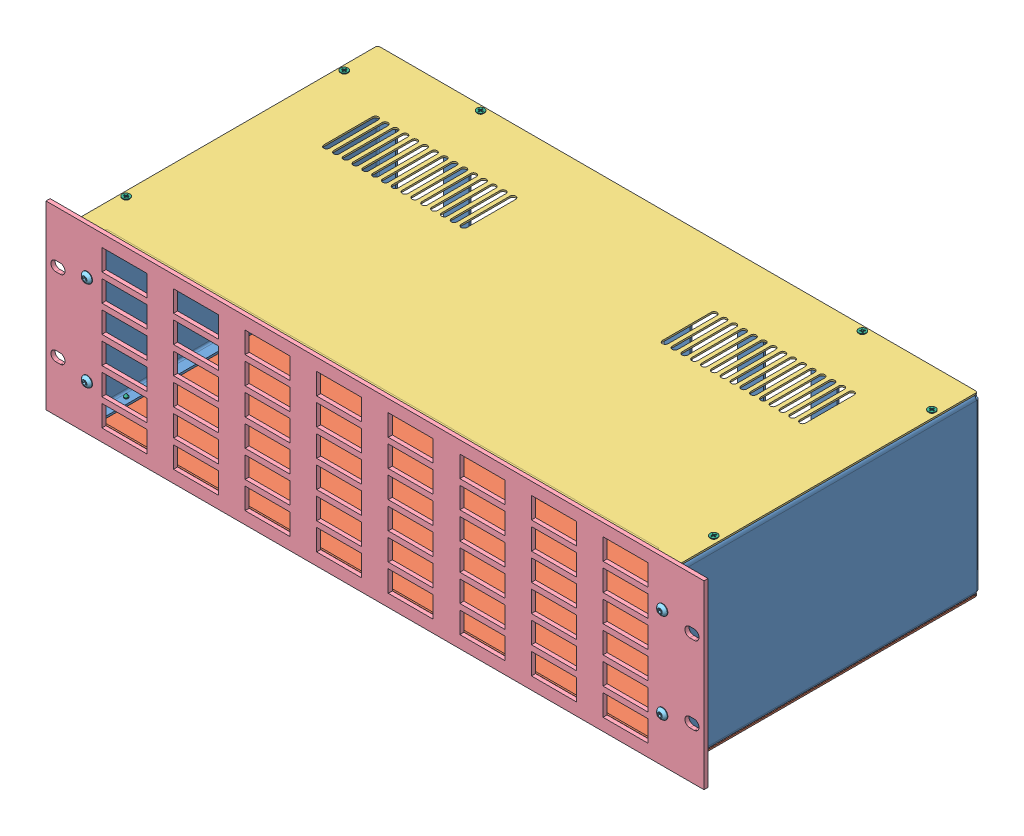
SolidWorks assembly Rack Wieland male, configuration R2100-3U. Lengths in mm.
Overall size (482.6 132.7 225.2).
20 component instances, 6 part files, 0 mates.
Components (placement in the parent):
- Frame 3U 8xHarting Female-1: Frame 3U 8xHarting Female [Default] at (0 0 -300) size (442 127 220)
- Penn Elcom-R2100-3U_R2100-R2110-Top-Base(R2100-005)-1: Penn Elcom-R2100-3U_R2100-R2110-Top-Base(R2100-005) [Default] at (0 -63.5 -80) x (-1 0 0) z (0 0 1) size (440 7.5 219)
- Penn Elcom-R2100-3U_R2100-R2110-Top-Base(R2100-006)-1: Penn Elcom-R2100-3U_R2100-R2110-Top-Base(R2100-006) [Default] at (0 63.5 -80) size (440 7.5 219)
- Rack 3U front panel 48x wieland male-2: Rack 3U front panel 48x wieland male [Default] at (0 0 -80) size (482.6 132.7 3)
- Penn Elcom-R2100-3U_02-012-10 (M4 x 10 Button Head)(02-012-10)-1: Penn Elcom-R2100-3U_02-012-10 (M4 x 10 Button Head)(02-012-10) [Default] at (211 -33 -74.8) x (0 0 -1) z (1 0 0) size (12.2 7.6 7.6)
- Penn Elcom-R2100-3U_02-012-10 (M4 x 10 Button Head)(02-012-10)-2: Penn Elcom-R2100-3U_02-012-10 (M4 x 10 Button Head)(02-012-10) [Default] at (211 33 -74.8) x (0 0 -1) z (1 0 0) size (12.2 7.6 7.6)
- Penn Elcom-R2100-3U_02-012-10 (M4 x 10 Button Head)(02-012-10)-3: Penn Elcom-R2100-3U_02-012-10 (M4 x 10 Button Head)(02-012-10) [Default] at (-211 33 -74.8) x (0 0 -1) z (1 0 0) size (12.2 7.6 7.6)
- Penn Elcom-R2100-3U_02-012-10 (M4 x 10 Button Head)(02-012-10)-4: Penn Elcom-R2100-3U_02-012-10 (M4 x 10 Button Head)(02-012-10) [Default] at (-211 -33 -74.8) x (0 0 -1) z (1 0 0) size (12.2 7.6 7.6)
- Penn Elcom-R2100-3U_01-023-10 (No4x6 CSK)-1: Penn Elcom-R2100-3U_01-023-10 (No4x6 CSK) [Default] at (-140 -65.85 -294.5) x (0 1 0) z (0 0 1) size (6.51 5.5 5.5)
- Penn Elcom-R2100-3U_01-023-10 (No4x6 CSK)-2: Penn Elcom-R2100-3U_01-023-10 (No4x6 CSK) [Default] at (215.5 -65.85 -270) x (0 1 0) z (0 0 1) size (6.51 5.5 5.5)
- Penn Elcom-R2100-3U_01-023-10 (No4x6 CSK)-3: Penn Elcom-R2100-3U_01-023-10 (No4x6 CSK) [Default] at (-215.5 65.85 -110) x (0 -1 0) z (0.087154 0 0.996195) size (6.51 5.5 5.5)
- Penn Elcom-R2100-3U_01-023-10 (No4x6 CSK)-4: Penn Elcom-R2100-3U_01-023-10 (No4x6 CSK) [Default] at (-215.5 65.85 -270) x (0 -1 0) z (0 0 1) size (6.51 5.5 5.5)
- Penn Elcom-R2100-3U_01-023-10 (No4x6 CSK)-5: Penn Elcom-R2100-3U_01-023-10 (No4x6 CSK) [Default] at (-215.5 -65.85 -110) x (0 1 0) z (0 0 1) size (6.51 5.5 5.5)
- Penn Elcom-R2100-3U_01-023-10 (No4x6 CSK)-6: Penn Elcom-R2100-3U_01-023-10 (No4x6 CSK) [Default] at (140 -65.85 -294.5) x (0 1 0) z (0 0 1) size (6.51 5.5 5.5)
- Penn Elcom-R2100-3U_01-023-10 (No4x6 CSK)-7: Penn Elcom-R2100-3U_01-023-10 (No4x6 CSK) [Default] at (215.5 -65.85 -110) x (0 1 0) z (0.678508 0 0.734593) size (6.51 5.5 5.5)
- Penn Elcom-R2100-3U_01-023-10 (No4x6 CSK)-8: Penn Elcom-R2100-3U_01-023-10 (No4x6 CSK) [Default] at (-215.5 -65.85 -270) x (0 1 0) z (0 0 1) size (6.51 5.5 5.5)
- Penn Elcom-R2100-3U_01-023-10 (No4x6 CSK)-9: Penn Elcom-R2100-3U_01-023-10 (No4x6 CSK) [Default] at (215.5 65.85 -110) x (0 -1 0) z (-0.257325 0 0.966325) size (6.51 5.5 5.5)
- Penn Elcom-R2100-3U_01-023-10 (No4x6 CSK)-10: Penn Elcom-R2100-3U_01-023-10 (No4x6 CSK) [Default] at (215.5 65.85 -270) x (0 -1 0) z (0 0 1) size (6.51 5.5 5.5)
- Penn Elcom-R2100-3U_01-023-10 (No4x6 CSK)-11: Penn Elcom-R2100-3U_01-023-10 (No4x6 CSK) [Default] at (-140 65.85 -294.5) x (0 -1 0) z (0 0 1) size (6.51 5.5 5.5)
- Penn Elcom-R2100-3U_01-023-10 (No4x6 CSK)-12: Penn Elcom-R2100-3U_01-023-10 (No4x6 CSK) [Default] at (140 65.85 -294.5) x (0 -1 0) z (0.664633 0 -0.74717) size (6.51 5.5 5.5)
